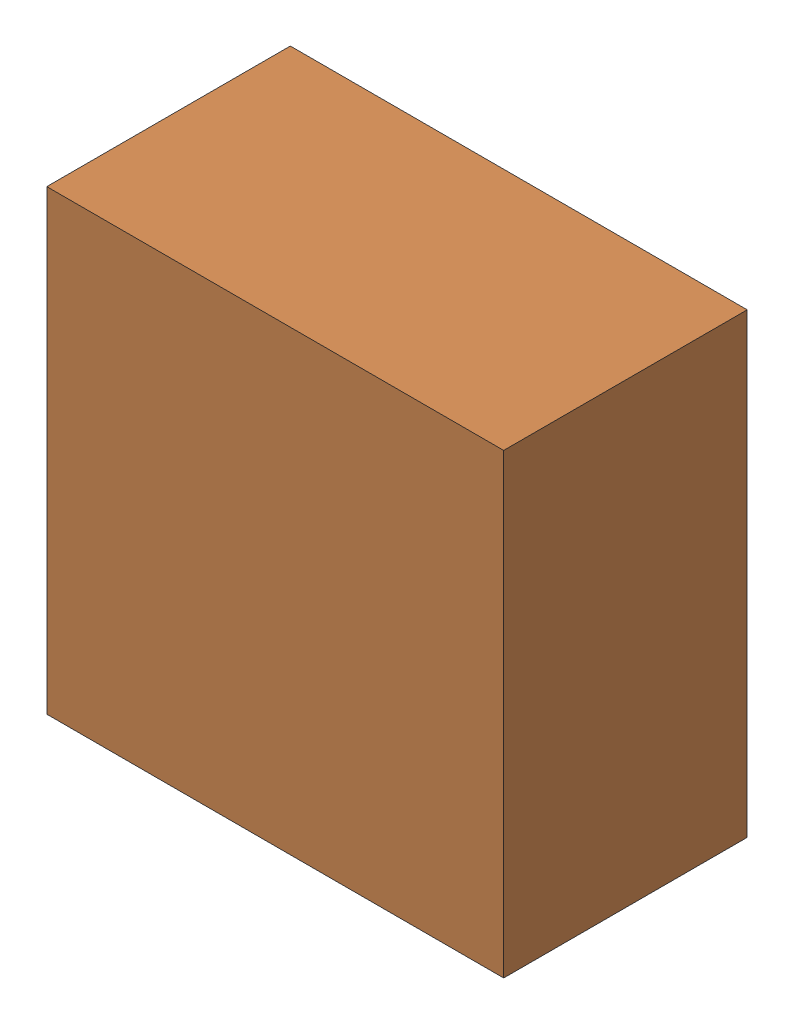
SolidWorks assembly U8, configuration Default. Lengths in mm.
Overall size (1 1 0.54).
4 component instances, 2 part files, 0 mates.
Components (placement in the parent):
- 756978528-1: 756978528 [Default] at (21.0001 56.5 -0.6115) x (0 -1 0) z (0 0 -1) size (0.1 0.1 0.39)
  - Cylinder (1)-1: Cylinder (1) [Default] at origin size (0.1 0.1 0.39)
- 676625568-1: 676625568 [Default] at (20.65 56.15 -0.9945) size (1 1 0.53)
  - Extruded (7)-1: Extruded (7) [Default] at origin size (1 1 0.53)
